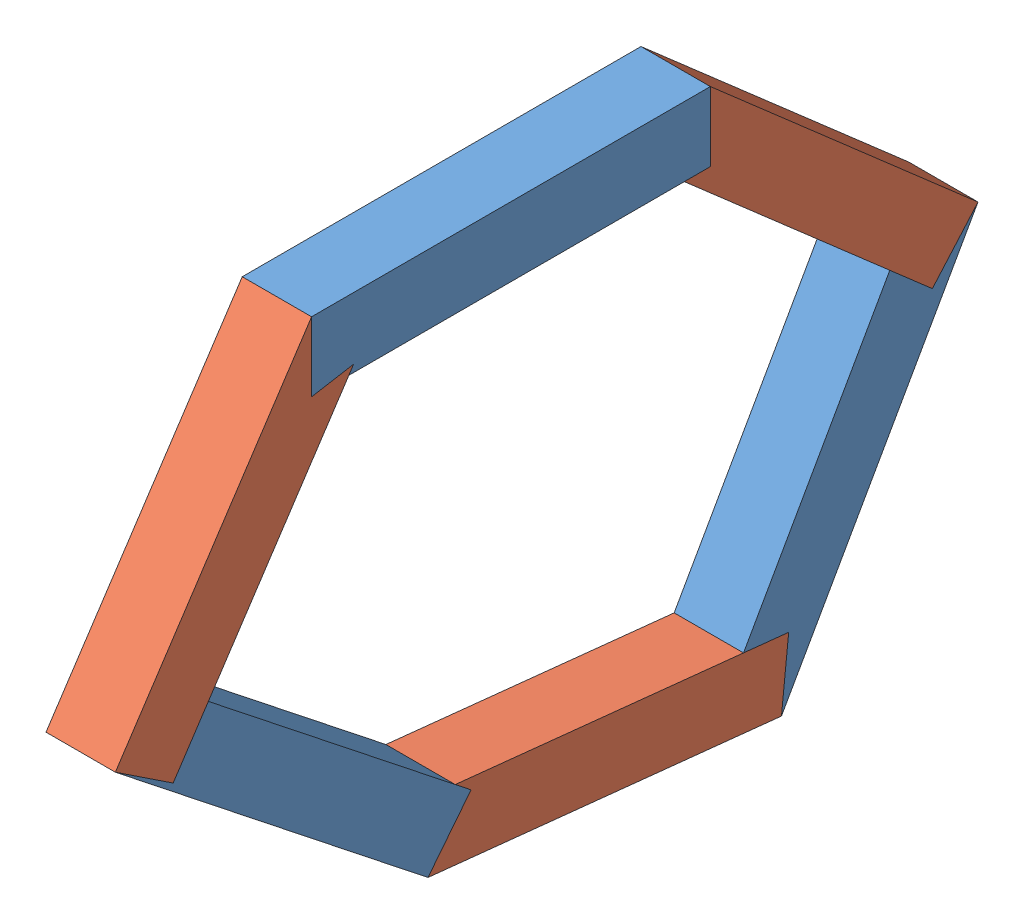
SolidWorks assembly sliding base channel, configuration Default. Lengths in mm.
Overall size (40 334.99 497.58).
6 component instances, 2 part files, 11 mates.
Components (placement in the parent):
- 160 mm 4 cm channel-1: 160 mm 4 cm channel [Default] at (57.5257 355.3371 31.6261) size (40 40 230)
- 205 mm 4 cm channel-1: 205 mm 4 cm channel [Default] at (57.5257 193.3767 358.1425) x (1 0 0) z (0 0.552153 0.833743) size (40 205 40)
- 160 mm 4 cm channel-2: 160 mm 4 cm channel [Default] at (57.5257 220.1011 362.4039) x (1 0 0) z (0 -0.620672 -0.784071) size (40 40 230)
- 205 mm 4 cm channel-2: 205 mm 4 cm channel [Default] at (57.5257 60.2396 -11.4873) x (1 0 0) z (0 -0.994579 0.103987) size (40 205 40)
- 160 mm 4 cm channel-3: 160 mm 4 cm channel [Default] at (57.5257 250.3302 -105.3631) x (1 0 0) z (0 -0.870109 0.49286) size (40 40 230)
- 205 mm 4 cm channel-3: 205 mm 4 cm channel [Default] at (57.5257 225.4104 -109.6078) x (1 0 0) z (0 -0.753129 0.657873) size (40 205 40)
Mates (geometry in assembly coordinates):
- Coincident1: coincident: point of 160 mm 4 cm channel-1; point of 205 mm 4 cm channel-1
- Coincident2: coincident: point of 160 mm 4 cm channel-1; point of 205 mm 4 cm channel-1
- Coincident3: coincident: point of 205 mm 4 cm channel-1; point of 160 mm 4 cm channel-2
- Coincident4: coincident: point of 205 mm 4 cm channel-1; point of 160 mm 4 cm channel-2
- Coincident5: coincident: point of 160 mm 4 cm channel-2; point of 205 mm 4 cm channel-2
- Coincident6: coincident: point of 160 mm 4 cm channel-2; point of 205 mm 4 cm channel-2
- Coincident7: coincident: point of 205 mm 4 cm channel-2; point of 160 mm 4 cm channel-3
- Coincident10: coincident: point of 205 mm 4 cm channel-2; point of 160 mm 4 cm channel-3
- Coincident11: coincident: point of 160 mm 4 cm channel-3; point of 205 mm 4 cm channel-3
- Coincident12: coincident: point of 160 mm 4 cm channel-3; point of 205 mm 4 cm channel-3
- Coincident13: coincident: point of 160 mm 4 cm channel-1; point of 205 mm 4 cm channel-3
